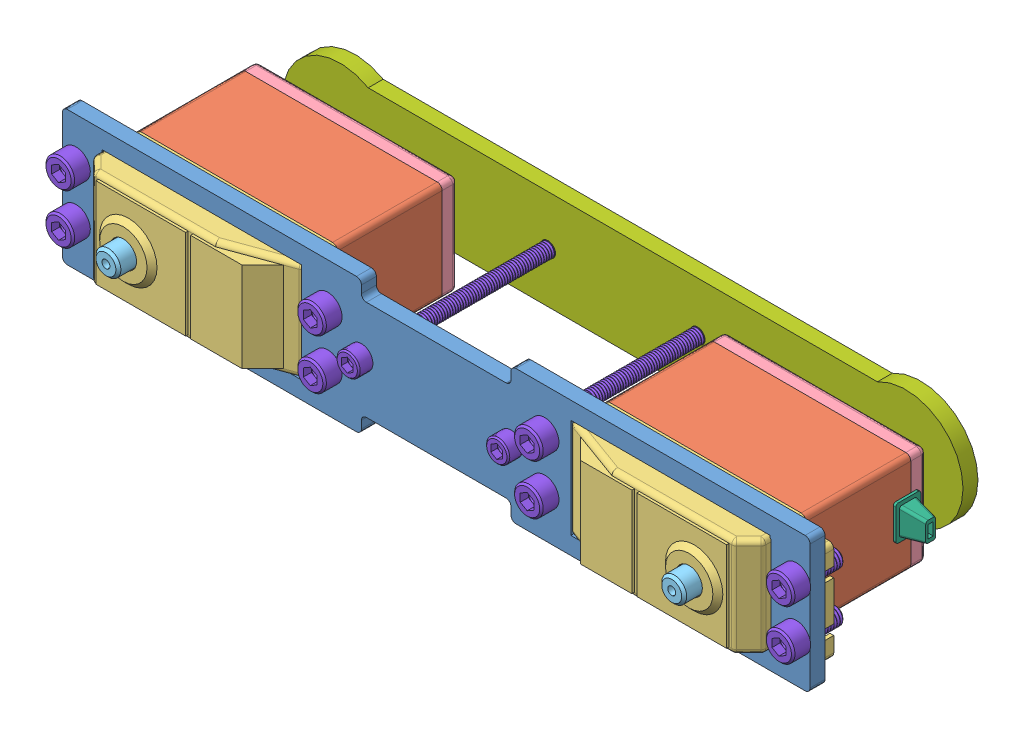
SolidWorks assembly link_2_littleRobot, configuration Predeterminado. Lengths in mm.
Overall size (150.24 126.5 50.43).
28 component instances, 10 part files, 36 mates.
Components (placement in the parent):
- C_pieza_arm_robot_v0-1: C_pieza_arm_robot_v0 [Predeterminado] at (75 13.5 -3) x (-1 0 0) z (0 0 1) size (150 27 3)
- Servomoteur Futuba S3003-2: Servomoteur Futuba S3003 [Défaut] at (122.3857 53.9 -11.7358) x (1 0 0) z (0 -1 0) size (55.5 42.98 32.41)
  - Boitier-1: Boitier [Défaut] at (8.3252 -16.2642 40.4) size (40.4 21 20)
  - Couvercle supérieure-1: Couvercle supérieure [Défaut] at (9.3643 6.7358 40.4) size (55.5 13 20)
  - Couvercle inférieure-1: Couvercle inférieure [Défaut] at (4.9957 -19.3642 40.4) size (40.4 3.1 20)
  - Axe-1: Axe [Défaut] at (9.3643 15.2358 40.4) size (5 16 5)
  - Passe fil-1: Passe fil [Défaut] at (17.8143 -15.2642 40.4) x (0 0 -1) z (1 0 0) size (7 5 7.5)
  - Palonnier-1: Palonnier [Défaut] at (9.3643 21.7358 40.4) x (0.465117 0 -0.885249) z (0 1 0) size (24 24 5) (hidden)
  - Vis CBL Z, M 2.5 - 5-1: Vis CBL Z, M 2.5 - 5 [Défaut] at (9.3643 21.7358 40.4) x (0.991239 0 0.132079) z (0 1 0) size (5 5 6.88) (hidden)
- Servomoteur Futuba S3003-3: Servomoteur Futuba S3003 [Défaut] at (27.6143 -26.9 -11.7358) x (-1 0 0) z (0 1 0) size (55.5 42.98 32.41)
  - Boitier-1: Boitier [Défaut] at (8.3252 -16.2642 40.4) size (40.4 21 20)
  - Couvercle supérieure-1: Couvercle supérieure [Défaut] at (9.3643 6.7358 40.4) size (55.5 13 20)
  - Couvercle inférieure-1: Couvercle inférieure [Défaut] at (4.9957 -19.3642 40.4) size (40.4 3.1 20)
  - Axe-1: Axe [Défaut] at (9.3643 15.2358 40.4) size (5 16 5)
  - Passe fil-1: Passe fil [Défaut] at (17.8143 -15.2642 40.4) x (0 0 -1) z (1 0 0) size (7 5 7.5)
  - Palonnier-1: Palonnier [Défaut] at (9.3643 21.7358 40.4) x (0.465117 0 -0.885249) z (0 1 0) size (24 24 5) (hidden)
  - Vis CBL Z, M 2.5 - 5-1: Vis CBL Z, M 2.5 - 5 [Défaut] at (9.3643 21.7358 40.4) x (0.991239 0 0.132079) z (0 1 0) size (5 5 6.88) (hidden)
- E_pieza_arm_robot_v0-1: E_pieza_arm_robot_v0 [Predeterminado] at (75 13.5 -40.432) x (0 -1 0) z (0 0 1) size (23 136.5 3)
- socket head cap screw_ai-11: socket head cap screw_ai [HX-SHCS 0.112-48x1.5x1.5-S] at (60 13.5 2.8448) x (0 0 -1) z (1 0 0) size (40.94 4.65 4.65)
- socket head cap screw_ai-12: socket head cap screw_ai [HX-SHCS 0.112-48x1.5x1.5-S] at (90 13.5 2.8448) x (0 0 -1) z (1 0 0) size (40.94 4.65 4.65)
- socket head cap screw_ai-14: socket head cap screw_ai [HX-SHCS 0.138-40x0.3125x0.3125-S] at (53.25 18.5 3.5052) x (0 0 -1) z (1 0 0) size (11.44 5.74 5.74)
- socket head cap screw_ai-15: socket head cap screw_ai [HX-SHCS 0.138-40x0.3125x0.3125-S] at (53.25 8.5 3.5052) x (0 0 -1) z (1 0 0) size (11.44 5.74 5.74)
- socket head cap screw_ai-16: socket head cap screw_ai [HX-SHCS 0.138-40x0.3125x0.3125-S] at (2.75 18.5 3.5052) x (0 0 -1) z (1 0 0) size (11.44 5.74 5.74)
- socket head cap screw_ai-17: socket head cap screw_ai [HX-SHCS 0.138-40x0.3125x0.3125-S] at (2.75 8.5 3.5052) x (0 0 -1) z (1 0 0) size (11.44 5.74 5.74)
- socket head cap screw_ai-18: socket head cap screw_ai [HX-SHCS 0.138-40x0.3125x0.3125-S] at (96.75 18.5 3.5052) x (0 0 -1) z (1 0 0) size (11.44 5.74 5.74)
- socket head cap screw_ai-19: socket head cap screw_ai [HX-SHCS 0.138-40x0.3125x0.3125-S] at (96.75 8.5 3.5052) x (0 0 -1) z (1 0 0) size (11.44 5.74 5.74)
- socket head cap screw_ai-20: socket head cap screw_ai [HX-SHCS 0.138-40x0.3125x0.3125-S] at (147.25 18.5 3.5052) x (0 0 -1) z (1 0 0) size (11.44 5.74 5.74)
- socket head cap screw_ai-21: socket head cap screw_ai [HX-SHCS 0.138-40x0.3125x0.3125-S] at (147.25 8.5 3.5052) x (0 0 -1) z (1 0 0) size (11.44 5.74 5.74)
Mates (geometry in assembly coordinates):
- Coincidente13: coincident anti-aligned: plane of C_pieza_arm_robot_v0-1 through (75 13.5 -3) normal (0 0 -1); plane of Servomoteur Futuba S3003-2/Couvercle supérieure-1 through (96.75 18.5 -3) normal (0 0 1)
- Concéntrica6: concentric anti-aligned: cylinder of C_pieza_arm_robot_v0-1 through (147.25 8.5 -3) axis (0 0 1) radius 2; cylinder of Servomoteur Futuba S3003-2/Couvercle supérieure-1 through (147.25 8.5 -3) axis (0 0 -1) radius 2
- Concéntrica7: concentric anti-aligned: cylinder of C_pieza_arm_robot_v0-1 through (147.25 18.5 -3) axis (0 0 1) radius 2; cylinder of Servomoteur Futuba S3003-2/Couvercle supérieure-1 through (147.25 18.5 -3) axis (0 0 -1) radius 2
- Coincidente14: coincident anti-aligned: plane of C_pieza_arm_robot_v0-1 through (75 13.5 -3) normal (0 0 -1); plane of Servomoteur Futuba S3003-3/Couvercle supérieure-1 through (53.25 8.5 -3) normal (0 0 1)
- Concéntrica8: concentric anti-aligned: cylinder of C_pieza_arm_robot_v0-1 through (2.75 8.5 -3) axis (0 0 1) radius 2; cylinder of Servomoteur Futuba S3003-3/Couvercle supérieure-1 through (2.75 8.5 -3) axis (0 0 -1) radius 2
- Concéntrica9: concentric anti-aligned: cylinder of C_pieza_arm_robot_v0-1 through (2.75 18.5 -3) axis (0 0 1) radius 2; cylinder of Servomoteur Futuba S3003-3/Couvercle supérieure-1 through (2.75 18.5 -3) axis (0 0 -1) radius 2
- Paralelo3: parallel aligned: plane of C_pieza_arm_robot_v0-1 through (60 3.5 0) normal (0 -1 0); plane of E_pieza_arm_robot_v0-1 through (75 3.5 -37.432) normal (0 -1 0)
- Concéntrica31: concentric aligned: cylinder of C_pieza_arm_robot_v0-1 through (60 13.5 -3) axis (0 0 1) radius 1.5; cylinder of socket head cap screw_ai-7 through (64.7787 129.0283 0.1988) axis (0.763622 0 0.645663) radius 2.3241
- Coincidente36: coincident anti-aligned: plane of C_pieza_arm_robot_v0-1 through (75 13.5 0) normal (0 0 1); plane of socket head cap screw_ai-7 through (38.3613 131.3524 -22.1378) normal (-0.763622 0 -0.645663)
- Concéntrica32: concentric aligned: cylinder of C_pieza_arm_robot_v0-1 through (90 13.5 -3) axis (0 0 1) radius 1.5; cylinder of socket head cap screw_ai-9 through (84.113 130.8451 -22.6678) axis (0.763622 0 0.645663) radius 2.3241
- Coincidente38: coincident anti-aligned: plane of C_pieza_arm_robot_v0-1 through (75 13.5 0) normal (0 0 1); plane of socket head cap screw_ai-9 through (57.6956 133.1692 -45.0044) normal (-0.763622 0 -0.645663)
- Concéntrica34: concentric aligned: cylinder of C_pieza_arm_robot_v0-1 through (60 13.5 -3) axis (0 0 1) radius 1.5; cylinder of socket head cap screw_ai-11 through (60 13.5 34.5948) axis (0 0 1) radius 2.3241
- Coincidente40: coincident anti-aligned: plane of C_pieza_arm_robot_v0-1 through (75 13.5 0) normal (0 0 1); plane of socket head cap screw_ai-11 through (60 15.8241 0) normal (0 0 -1)
- Concéntrica35: concentric aligned: cylinder of C_pieza_arm_robot_v0-1 through (90 13.5 -3) axis (0 0 1) radius 1.5; cylinder of socket head cap screw_ai-12 through (90 13.5 34.5948) axis (0 0 1) radius 2.3241
- Coincidente41: coincident anti-aligned: plane of C_pieza_arm_robot_v0-1 through (75 13.5 0) normal (0 0 1); plane of socket head cap screw_ai-12 through (90 15.8241 0) normal (0 0 -1)
- Concéntrica37: concentric aligned: cylinder of C_pieza_arm_robot_v0-1 through (53.25 18.5 -3) axis (0 0 1) radius 2; cylinder of socket head cap screw_ai-14 through (53.25 18.5 35.2552) axis (0 0 1) radius 2.8702
- Coincidente43: coincident anti-aligned: plane of C_pieza_arm_robot_v0-1 through (75 13.5 0) normal (0 0 1); plane of socket head cap screw_ai-14 through (53.25 21.3702 0) normal (0 0 -1)
- Concéntrica38: concentric aligned: cylinder of C_pieza_arm_robot_v0-1 through (53.25 8.5 -3) axis (0 0 1) radius 2; cylinder of socket head cap screw_ai-15 through (53.25 8.5 35.2552) axis (0 0 1) radius 2.8702
- Coincidente44: coincident anti-aligned: plane of C_pieza_arm_robot_v0-1 through (75 13.5 0) normal (0 0 1); plane of socket head cap screw_ai-15 through (53.25 11.3702 0) normal (0 0 -1)
- Concéntrica39: concentric aligned: cylinder of C_pieza_arm_robot_v0-1 through (2.75 18.5 -3) axis (0 0 1) radius 2; cylinder of socket head cap screw_ai-16 through (2.75 18.5 35.2552) axis (0 0 1) radius 2.8702
- Coincidente45: coincident anti-aligned: plane of C_pieza_arm_robot_v0-1 through (75 13.5 0) normal (0 0 1); plane of socket head cap screw_ai-16 through (2.75 21.3702 0) normal (0 0 -1)
- Concéntrica40: concentric aligned: cylinder of C_pieza_arm_robot_v0-1 through (2.75 8.5 -3) axis (0 0 1) radius 2; cylinder of socket head cap screw_ai-17 through (2.75 8.5 35.2552) axis (0 0 1) radius 2.8702
- Coincidente46: coincident anti-aligned: plane of C_pieza_arm_robot_v0-1 through (75 13.5 0) normal (0 0 1); plane of socket head cap screw_ai-17 through (2.75 11.3702 0) normal (0 0 -1)
- Concéntrica41: concentric aligned: cylinder of C_pieza_arm_robot_v0-1 through (96.75 18.5 -3) axis (0 0 1) radius 2; cylinder of socket head cap screw_ai-18 through (96.75 18.5 35.2552) axis (0 0 1) radius 2.8702
- Coincidente47: coincident anti-aligned: plane of C_pieza_arm_robot_v0-1 through (75 13.5 0) normal (0 0 1); plane of socket head cap screw_ai-18 through (96.75 21.3702 0) normal (0 0 -1)
- Concéntrica42: concentric aligned: cylinder of C_pieza_arm_robot_v0-1 through (96.75 8.5 -3) axis (0 0 1) radius 2; cylinder of socket head cap screw_ai-19 through (96.75 8.5 35.2552) axis (0 0 1) radius 2.8702
- Coincidente48: coincident anti-aligned: plane of C_pieza_arm_robot_v0-1 through (75 13.5 0) normal (0 0 1); plane of socket head cap screw_ai-19 through (96.75 11.3702 0) normal (0 0 -1)
- Concéntrica43: concentric aligned: cylinder of C_pieza_arm_robot_v0-1 through (147.25 18.5 -3) axis (0 0 1) radius 2; cylinder of socket head cap screw_ai-20 through (147.25 18.5 35.2552) axis (0 0 1) radius 2.8702
- Coincidente49: coincident anti-aligned: plane of C_pieza_arm_robot_v0-1 through (75 13.5 0) normal (0 0 1); plane of socket head cap screw_ai-20 through (147.25 21.3702 0) normal (0 0 -1)
- Concéntrica44: concentric aligned: cylinder of C_pieza_arm_robot_v0-1 through (147.25 8.5 -3) axis (0 0 1) radius 2; cylinder of socket head cap screw_ai-21 through (147.25 8.5 35.2552) axis (0 0 1) radius 2.8702
- Coincidente50: coincident anti-aligned: plane of C_pieza_arm_robot_v0-1 through (75 13.5 0) normal (0 0 1); plane of socket head cap screw_ai-21 through (147.25 11.3702 0) normal (0 0 -1)
- Distancia1: distance = 6.332 mm anti-aligned: plane of E_pieza_arm_robot_v0-1 through (75 13.5 -37.432) normal (0 0 1); plane of Servomoteur Futuba S3003-3/Couvercle inférieure-1 through (22.6186 13.5 -31.1) normal (0 0 -1)
- Concéntrica46: concentric aligned: cylinder of E_pieza_arm_robot_v0-1 through (60 13.5 -40.432) axis (0 0 1) radius 1.5; cylinder of socket head cap screw_ai-11 through (60 13.5 34.5948) axis (0 0 1) radius 2.3241
- Coincidente52: coincident aligned: plane of C_pieza_arm_robot_v0-1 through (75 13.5 0) normal (0 0 1)
- Coincidente53: coincident anti-aligned: plane of C_pieza_arm_robot_v0-1 through (90 0 0) normal (0 -1 0)
- Coincidente54: coincident anti-aligned: plane of C_pieza_arm_robot_v0-1 through (0 0 0) normal (-1 0 0)
